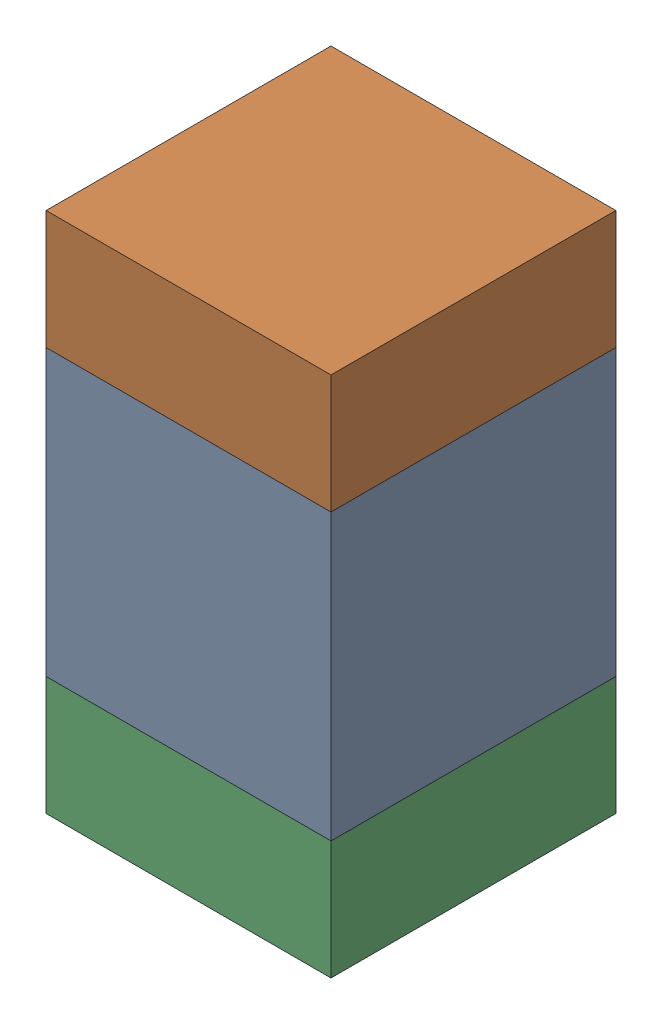
SolidWorks assembly C111_2PCB, configuration Default. Lengths in mm.
Overall size (0.6 1.1 0.6).
6 component instances, 2 part files, 0 mates.
Components (placement in the parent):
- 761606048-1: 761606048 [Default] at (116.7 93.7 0) size (0.6 0.6 0.6)
  - Extruded_9-1: Extruded_9 [Default] at origin size (0.6 0.6 0.6)
- 854785296-1: 854785296 [Default] at (116.7 94.125 0) size (0.6 0.25 0.6)
  - Extruded_10-1: Extruded_10 [Default] at origin size (0.6 0.25 0.6)
- 854785296-2: 854785296 [Default] at (116.7 93.275 0) size (0.6 0.25 0.6)
  - Extruded_10-1: Extruded_10 [Default] at origin size (0.6 0.25 0.6)
